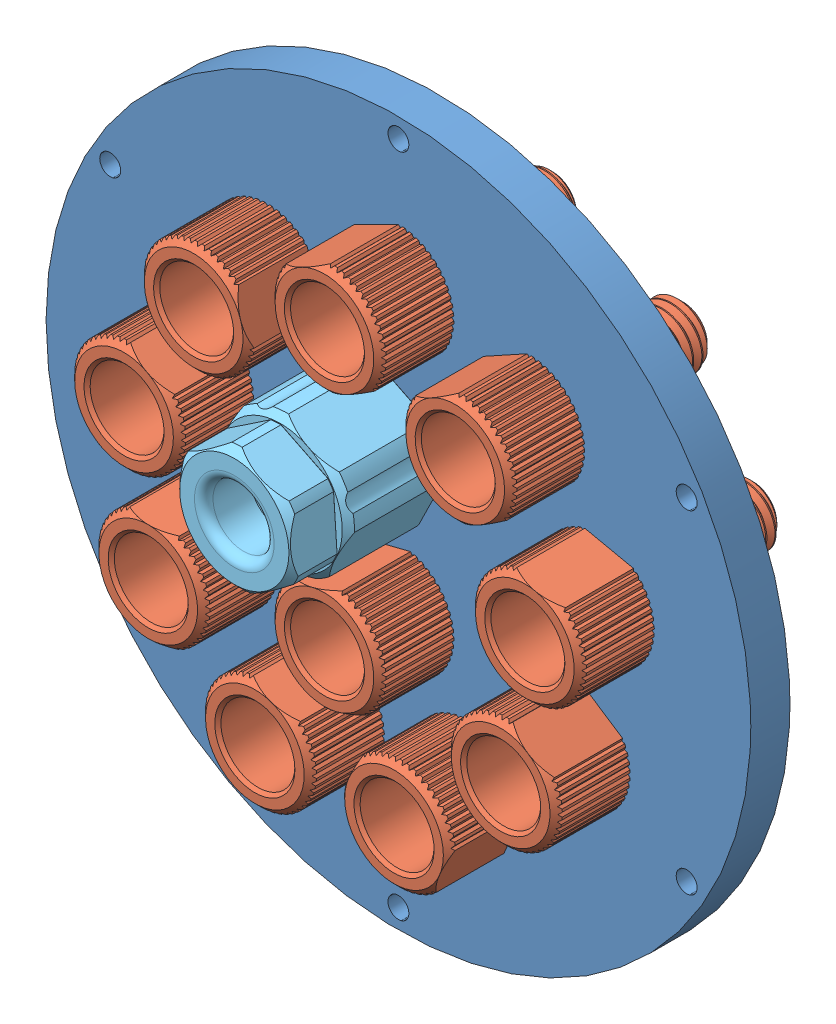
SolidWorks assembly penetrator_assembly_m10x10_m14x1, configuration Default. Lengths in mm.
Overall size (114.3 114.3 48.53).
23 component instances, 5 part files, 44 mates.
Components (placement in the parent):
- end_cap_M10x10,M14x1-1: end_cap_M10x10,M14x1 [Default] at (10.4541 5.3088 -12.2982) size (114.3 114.3 6.35)
- PENETRATOR-M-BOLT-6MM-10-25-R2-1: PENETRATOR-M-BOLT-6MM-10-25-R2 [Default] at (-10.7579 30.5882 -5.9482) x (-0.310028 0.950727 0) z (0 0 1) size (18 16 37.53)
- PENETRATOR-M-NUT-10-8-R2-1: PENETRATOR-M-NUT-10-8-R2 [Default] at (-10.7579 30.5882 -20.2982) x (0.617696 0.786417 0) z (0 0 1) size (18 16 9.22)
- PENETRATOR-M-BOLT-6MM-10-25-R2-2: PENETRATOR-M-BOLT-6MM-10-25-R2 [Default] at (-22.0446 11.0392 -5.9482) x (-0.887897 0.460042 0) z (0 0 1) size (18 16 37.53)
- PENETRATOR-M-NUT-10-8-R2-2: PENETRATOR-M-NUT-10-8-R2 [Default] at (-22.0446 11.0392 -20.2982) x (0.290918 0.956748 0) z (0 0 1) size (18 16 9.22)
- WL-M14-NUT-PUBLIC-2: WL-M14-NUT-PUBLIC [Default] at (6.8379 15.2442 -16.2982) x (0 0 -1) z (0.666982 0.745074 0) size (8.01 20 20.58)
- WLP-M14-9.5MM-PUBLIC-2: WLP-M14-9.5MM-PUBLIC [Default] at (6.8379 15.2442 -30.9482) x (0.441162 0.897427 0) z (0.897427 -0.441162 0) size (20 48.41 21.41)
- PENETRATOR-M-NUT-10-8-R2-4: PENETRATOR-M-NUT-10-8-R2 [Default] at (10.4541 -6.4442 -20.2982) x (0.998805 -0.04888 0) z (0 0 1) size (18 16 9.22)
- PENETRATOR-M-BOLT-6MM-10-25-R2-4: PENETRATOR-M-BOLT-6MM-10-25-R2 [Default] at (10.4541 -6.4442 -5.9482) x (0.969772 0.244012 0) z (0 0 1) size (18 16 37.53)
- PENETRATOR-M-BOLT-6MM-10-25-R2-5: PENETRATOR-M-BOLT-6MM-10-25-R2 [Default] at (21.7408 -25.7011 -5.9482) x (-0.382975 -0.923759 0) z (0 0 1) size (18 16 37.53)
- PENETRATOR-M-NUT-10-8-R2-5: PENETRATOR-M-NUT-10-8-R2 [Default] at (21.7408 -25.7011 -20.2982) x (-0.907422 -0.42022 0) z (0 0 1) size (18 16 9.22)
- PENETRATOR-M-BOLT-6MM-10-25-R2-6: PENETRATOR-M-BOLT-6MM-10-25-R2 [Default] at (39.0329 -11.1912 -5.9482) x (-0.834613 0.550836 0) z (0 0 1) size (18 16 37.53)
- PENETRATOR-M-BOLT-6MM-10-25-R2-7: PENETRATOR-M-BOLT-6MM-10-25-R2 [Default] at (42.9527 11.0392 -5.9482) x (-0.977727 0.20988 0) z (0 0 1) size (18 16 37.53)
- PENETRATOR-M-BOLT-6MM-10-25-R2-8: PENETRATOR-M-BOLT-6MM-10-25-R2 [Default] at (31.6661 30.5882 -5.9482) x (0.875632 0.482979 0) z (0 0 1) size (18 16 37.53)
- PENETRATOR-M-BOLT-6MM-10-25-R2-9: PENETRATOR-M-BOLT-6MM-10-25-R2 [Default] at (10.4541 38.3088 -5.9482) x (-0.893227 -0.449606 0) z (0 0 1) size (18 16 37.53)
- PENETRATOR-M-BOLT-6MM-10-25-R2-10: PENETRATOR-M-BOLT-6MM-10-25-R2 [Default] at (-0.8326 -25.7011 -5.9482) x (0.945176 -0.326563 0) z (0 0 1) size (18 16 37.53)
- PENETRATOR-M-BOLT-6MM-10-25-R2-11: PENETRATOR-M-BOLT-6MM-10-25-R2 [Default] at (-18.1247 -11.1912 -5.9482) x (0.999971 -0.007679 0) z (0 0 1) size (18 16 37.53)
- PENETRATOR-M-NUT-10-8-R2-6: PENETRATOR-M-NUT-10-8-R2 [Default] at (10.4541 38.3088 -20.2982) x (-0.983846 -0.179019 0) z (0 0 1) size (18 16 9.22)
- PENETRATOR-M-NUT-10-8-R2-7: PENETRATOR-M-NUT-10-8-R2 [Default] at (31.6661 30.5882 -20.2982) x (0.809258 -0.587453 0) z (0 0 1) size (18 16 9.22)
- PENETRATOR-M-NUT-10-8-R2-8: PENETRATOR-M-NUT-10-8-R2 [Default] at (42.9527 11.0392 -20.2982) x (0.160591 -0.987021 0) z (0 0 1) size (18 16 9.22)
- PENETRATOR-M-NUT-10-8-R2-9: PENETRATOR-M-NUT-10-8-R2 [Default] at (39.0329 -11.1912 -20.2982) x (-0.450492 -0.89278 0) z (0 0 1) size (18 16 9.22)
- PENETRATOR-M-NUT-10-8-R2-10: PENETRATOR-M-NUT-10-8-R2 [Default] at (-18.1247 -11.1912 -20.2982) x (0.778823 -0.627244 0) z (0 0 1) size (18 16 9.22)
- PENETRATOR-M-NUT-10-8-R2-11: PENETRATOR-M-NUT-10-8-R2 [Default] at (-0.8326 -25.7011 -20.2982) x (-0.976669 0.214749 0) z (0 0 1) size (18 16 9.22)
Mates (geometry in assembly coordinates):
- Concentric3: concentric anti-aligned: circle of end_cap_M10x10,M14x1-1; circle of PENETRATOR-M-BOLT-6MM-10-25-R2-1
- Coincident3: coincident anti-aligned: plane of end_cap_M10x10,M14x1-1 through (10.4541 5.3088 -5.9482) normal (0 0 1); plane of PENETRATOR-M-BOLT-6MM-10-25-R2-1 through (-10.7579 30.5882 -5.9482) normal (0 0 -1)
- Concentric4: concentric anti-aligned: circle of PENETRATOR-M-BOLT-6MM-10-25-R2-1; circle of PENETRATOR-M-NUT-10-8-R2-1
- Coincident4: coincident anti-aligned: plane of end_cap_M10x10,M14x1-1 through (10.4541 5.3088 -12.2982) normal (0 0 -1); plane of PENETRATOR-M-NUT-10-8-R2-1 through (-10.7579 30.5882 -12.2982) normal (0 0 1)
- Concentric5: concentric anti-aligned: circle of end_cap_M10x10,M14x1-1; circle of PENETRATOR-M-BOLT-6MM-10-25-R2-2
- Coincident5: coincident anti-aligned: plane of end_cap_M10x10,M14x1-1 through (10.4541 5.3088 -5.9482) normal (0 0 1); plane of PENETRATOR-M-BOLT-6MM-10-25-R2-2 through (-22.0446 11.0392 -5.9482) normal (0 0 -1)
- Concentric6: concentric aligned: circle of PENETRATOR-M-BOLT-6MM-10-25-R2-2; circle of PENETRATOR-M-NUT-10-8-R2-2
- Coincident6: coincident anti-aligned: plane of end_cap_M10x10,M14x1-1 through (10.4541 5.3088 -12.2982) normal (0 0 -1); plane of PENETRATOR-M-NUT-10-8-R2-2 through (-22.0446 11.0392 -12.2982) normal (0 0 1)
- Coincident7: coincident anti-aligned: plane of end_cap_M10x10,M14x1-1 through (10.4541 5.3088 -12.2982) normal (0 0 -1); plane of WL-M14-NUT-PUBLIC-2 through (0.3015 7.9424 -12.2982) normal (0 0 1)
- Concentric7: concentric aligned: circle of end_cap_M10x10,M14x1-1; circle of WLP-M14-9.5MM-PUBLIC-2
- Coincident8: coincident anti-aligned: plane of end_cap_M10x10,M14x1-1 through (10.4541 5.3088 -5.9482) normal (0 0 1); plane of WLP-M14-9.5MM-PUBLIC-2 through (2.6027 6.6289 -5.9482) normal (0 0 -1)
- Concentric8: concentric anti-aligned: circle of WL-M14-NUT-PUBLIC-2; circle of WLP-M14-9.5MM-PUBLIC-2
- Concentric10: concentric aligned: circle of end_cap_M10x10,M14x1-1; circle of PENETRATOR-M-BOLT-6MM-10-25-R2-4
- Coincident10: coincident anti-aligned: plane of end_cap_M10x10,M14x1-1 through (10.4541 5.3088 -5.9482) normal (0 0 1); plane of PENETRATOR-M-BOLT-6MM-10-25-R2-4 through (10.4541 -6.4442 -5.9482) normal (0 0 -1)
- Concentric11: concentric aligned: circle of PENETRATOR-M-NUT-10-8-R2-4; circle of PENETRATOR-M-BOLT-6MM-10-25-R2-4
- Coincident11: coincident anti-aligned: plane of end_cap_M10x10,M14x1-1 through (10.4541 5.3088 -12.2982) normal (0 0 -1); plane of PENETRATOR-M-NUT-10-8-R2-4 through (10.4541 -6.4442 -12.2982) normal (0 0 1)
- Concentric12: concentric anti-aligned: circle of end_cap_M10x10,M14x1-1; circle of PENETRATOR-M-BOLT-6MM-10-25-R2-5
- Coincident13: coincident anti-aligned: plane of end_cap_M10x10,M14x1-1 through (10.4541 5.3088 -5.9482) normal (0 0 1); plane of PENETRATOR-M-BOLT-6MM-10-25-R2-5 through (21.7408 -25.7011 -5.9482) normal (0 0 -1)
- Concentric13: concentric anti-aligned: circle of end_cap_M10x10,M14x1-1; circle of PENETRATOR-M-NUT-10-8-R2-5
- Coincident14: coincident anti-aligned: plane of end_cap_M10x10,M14x1-1 through (10.4541 5.3088 -12.2982) normal (0 0 -1); plane of PENETRATOR-M-NUT-10-8-R2-5 through (21.7408 -25.7011 -12.2982) normal (0 0 1)
- Concentric14: concentric anti-aligned: circle of end_cap_M10x10,M14x1-1; circle of PENETRATOR-M-BOLT-6MM-10-25-R2-6
- Concentric15: concentric anti-aligned: circle of end_cap_M10x10,M14x1-1; circle of PENETRATOR-M-BOLT-6MM-10-25-R2-7
- Concentric16: concentric anti-aligned: circle of end_cap_M10x10,M14x1-1; circle of PENETRATOR-M-BOLT-6MM-10-25-R2-8
- Concentric17: concentric anti-aligned: circle of end_cap_M10x10,M14x1-1; circle of PENETRATOR-M-BOLT-6MM-10-25-R2-9
- Concentric18: concentric anti-aligned: circle of end_cap_M10x10,M14x1-1; circle of PENETRATOR-M-BOLT-6MM-10-25-R2-10
- Concentric19: concentric anti-aligned: circle of end_cap_M10x10,M14x1-1; circle of PENETRATOR-M-BOLT-6MM-10-25-R2-11
- Coincident15: coincident aligned: plane of PENETRATOR-M-BOLT-6MM-10-25-R2-10 through (-0.8326 -25.7011 -5.9482) normal (0 0 -1); plane of PENETRATOR-M-BOLT-6MM-10-25-R2-11 through (-18.1247 -11.1912 -5.9482) normal (0 0 -1)
- Coincident16: coincident aligned: plane of PENETRATOR-M-BOLT-6MM-10-25-R2-6 through (39.0329 -11.1912 -5.9482) normal (0 0 -1); plane of PENETRATOR-M-BOLT-6MM-10-25-R2-11 through (-18.1247 -11.1912 -5.9482) normal (0 0 -1)
- Coincident17: coincident aligned: plane of PENETRATOR-M-BOLT-6MM-10-25-R2-7 through (42.9527 11.0392 -5.9482) normal (0 0 -1); plane of PENETRATOR-M-BOLT-6MM-10-25-R2-11 through (-18.1247 -11.1912 -5.9482) normal (0 0 -1)
- Coincident18: coincident aligned: plane of PENETRATOR-M-BOLT-6MM-10-25-R2-8 through (31.6661 30.5882 -5.9482) normal (0 0 -1); plane of PENETRATOR-M-BOLT-6MM-10-25-R2-11 through (-18.1247 -11.1912 -5.9482) normal (0 0 -1)
- Coincident19: coincident aligned: plane of PENETRATOR-M-BOLT-6MM-10-25-R2-9 through (10.4541 38.3088 -5.9482) normal (0 0 -1); plane of PENETRATOR-M-BOLT-6MM-10-25-R2-11 through (-18.1247 -11.1912 -5.9482) normal (0 0 -1)
- Coincident20: coincident anti-aligned: plane of end_cap_M10x10,M14x1-1 through (10.4541 5.3088 -5.9482) normal (0 0 1); plane of PENETRATOR-M-BOLT-6MM-10-25-R2-9 through (10.4541 38.3088 -5.9482) normal (0 0 -1)
- Concentric20: concentric anti-aligned: circle of end_cap_M10x10,M14x1-1; circle of PENETRATOR-M-NUT-10-8-R2-11
- Concentric21: concentric anti-aligned: circle of end_cap_M10x10,M14x1-1; circle of PENETRATOR-M-NUT-10-8-R2-10
- Concentric22: concentric anti-aligned: circle of end_cap_M10x10,M14x1-1; circle of PENETRATOR-M-NUT-10-8-R2-9
- Concentric23: concentric anti-aligned: circle of end_cap_M10x10,M14x1-1; circle of PENETRATOR-M-NUT-10-8-R2-8
- Concentric24: concentric anti-aligned: circle of end_cap_M10x10,M14x1-1; circle of PENETRATOR-M-NUT-10-8-R2-7
- Concentric25: concentric anti-aligned: circle of end_cap_M10x10,M14x1-1; circle of PENETRATOR-M-NUT-10-8-R2-6
- Coincident21: coincident aligned: plane of PENETRATOR-M-NUT-10-8-R2-10 through (-18.1247 -11.1912 -12.2982) normal (0 0 1); plane of PENETRATOR-M-NUT-10-8-R2-11 through (-0.8326 -25.7011 -12.2982) normal (0 0 1)
- Coincident22: coincident aligned: plane of PENETRATOR-M-NUT-10-8-R2-9 through (39.0329 -11.1912 -12.2982) normal (0 0 1); plane of PENETRATOR-M-NUT-10-8-R2-11 through (-0.8326 -25.7011 -12.2982) normal (0 0 1)
- Coincident23: coincident aligned: plane of PENETRATOR-M-NUT-10-8-R2-8 through (42.9527 11.0392 -12.2982) normal (0 0 1); plane of PENETRATOR-M-NUT-10-8-R2-11 through (-0.8326 -25.7011 -12.2982) normal (0 0 1)
- Coincident24: coincident aligned: plane of PENETRATOR-M-NUT-10-8-R2-7 through (31.6661 30.5882 -12.2982) normal (0 0 1); plane of PENETRATOR-M-NUT-10-8-R2-11 through (-0.8326 -25.7011 -12.2982) normal (0 0 1)
- Coincident25: coincident aligned: plane of PENETRATOR-M-NUT-10-8-R2-6 through (10.4541 38.3088 -12.2982) normal (0 0 1); plane of PENETRATOR-M-NUT-10-8-R2-11 through (-0.8326 -25.7011 -12.2982) normal (0 0 1)
- Coincident26: coincident anti-aligned: plane of end_cap_M10x10,M14x1-1 through (10.4541 5.3088 -12.2982) normal (0 0 -1); plane of PENETRATOR-M-NUT-10-8-R2-9 through (39.0329 -11.1912 -12.2982) normal (0 0 1)
